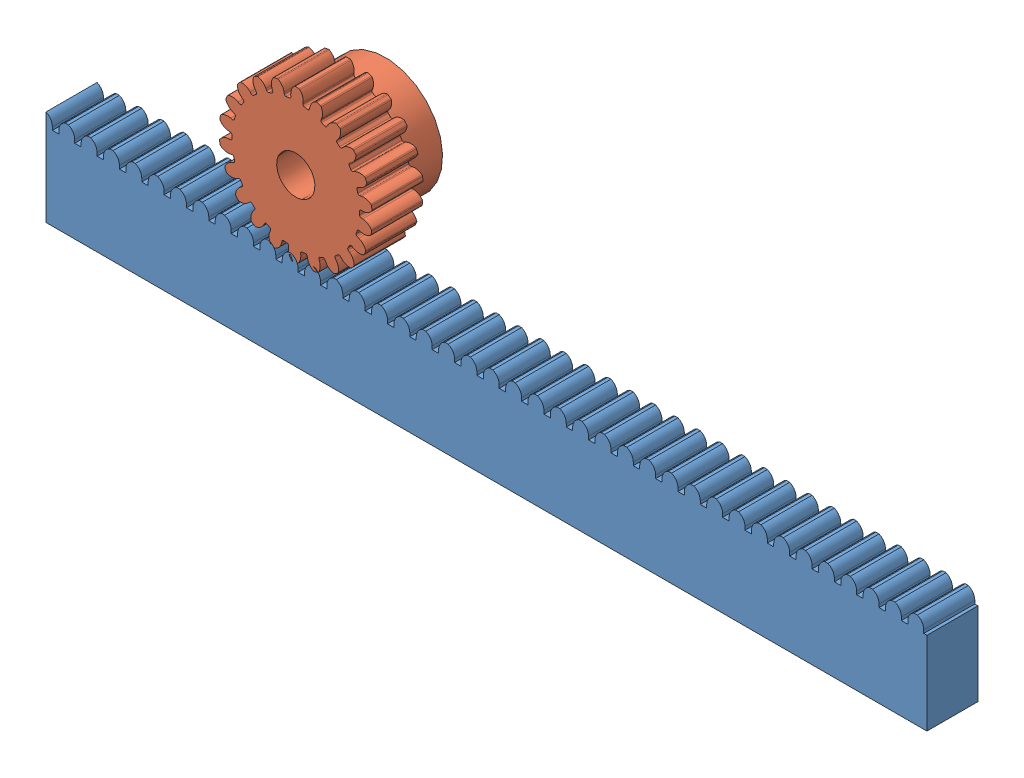
SolidWorks assembly Assemblage2, configuration Default. Lengths in mm.
Overall size (138 41.93 14).
2 component instances, 2 part files, 3 mates.
Components (placement in the parent):
- cremaillere_HPC_L138_module1-1: cremaillere_HPC_L138_module1 [Default] at (-73.2484 2.7577 -0.7271) size (138 15 8)
- pignon_HPC_D24_Z22_M6-1: pignon_HPC_D24_Z22_M6 [Défaut] at (-34.1225 28.7577 -0.7271) x (0 0 -1) z (0.902167 -0.431388 0) size (14 23.83 24)
Mates (geometry in assembly coordinates):
- Coïncidente1: coincident aligned: plane of cremaillere_HPC_L138_module1-1 through (-73.2484 17.7577 -0.7271) normal (0 0 1); plane of pignon_HPC_D24_Z22_M6-1 through (-34.1225 28.7577 -0.7271) normal (0 0 1)
- Distance3: distance = 2 mm anti-aligned: plane of cremaillere_HPC_L138_module1-1 through (-73.2484 17.7577 -8.7271) normal (0 1 0); cylinder of pignon_HPC_D24_Z22_M6-1
- Contrainte pignon-crémaillère1: rack pinion = 24 mm: line of cremaillere_HPC_L138_module1-1; circle of pignon_HPC_D24_Z22_M6-1
